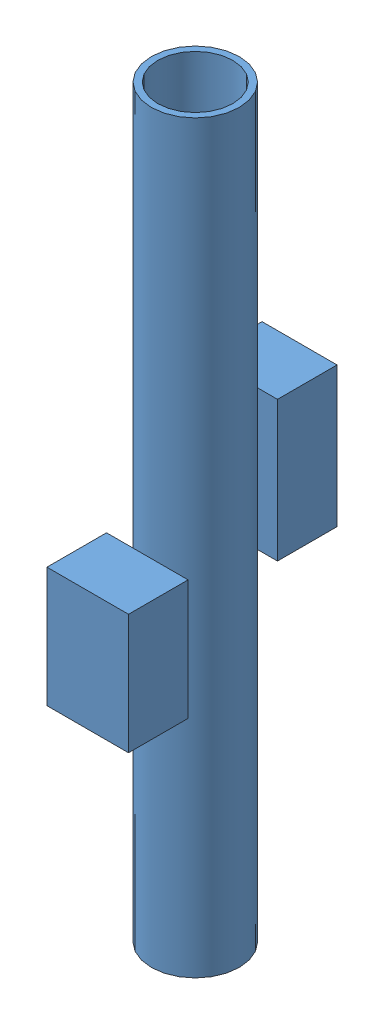
SolidWorks assembly Assem1, configuration Default. Lengths in mm.
Overall size (29.57 250 70).
7 component instances, 2 part files, 0 mates.
Components (placement in the parent):
- Part1-1: Part1 [Default] at (106.4402 40.0967 246.3661) size (29.57 250 70)
- Part2-2: Part2 [Default] at (104.457 162.9306 239.9293) x (0 -1 0) z (0 0 1) size (20 5 12)
- Part2-3: Part2 [Default] at (110.3334 167.6266 241.004) x (0 1 0) z (0 0 1) size (20 5 12)
- Part2-4: Part2 [Default] at (110.2168 188.947 241.162) x (0 1 0) z (0 0 1) size (20 5 12)
- Part2-5: Part2 [Default] at (110.5749 253.441 241.5001) x (0 1 0) z (0 0 1) size (20 5 12)
- Part2-6: Part2 [Default] at (110.2688 231.6683 241.2229) x (0 1 0) z (0 0 1) size (20 5 12)
- Part2-7: Part2 [Default] at (110.3906 210.2139 240.9907) x (0 1 0) z (0 0 1) size (20 5 12)
